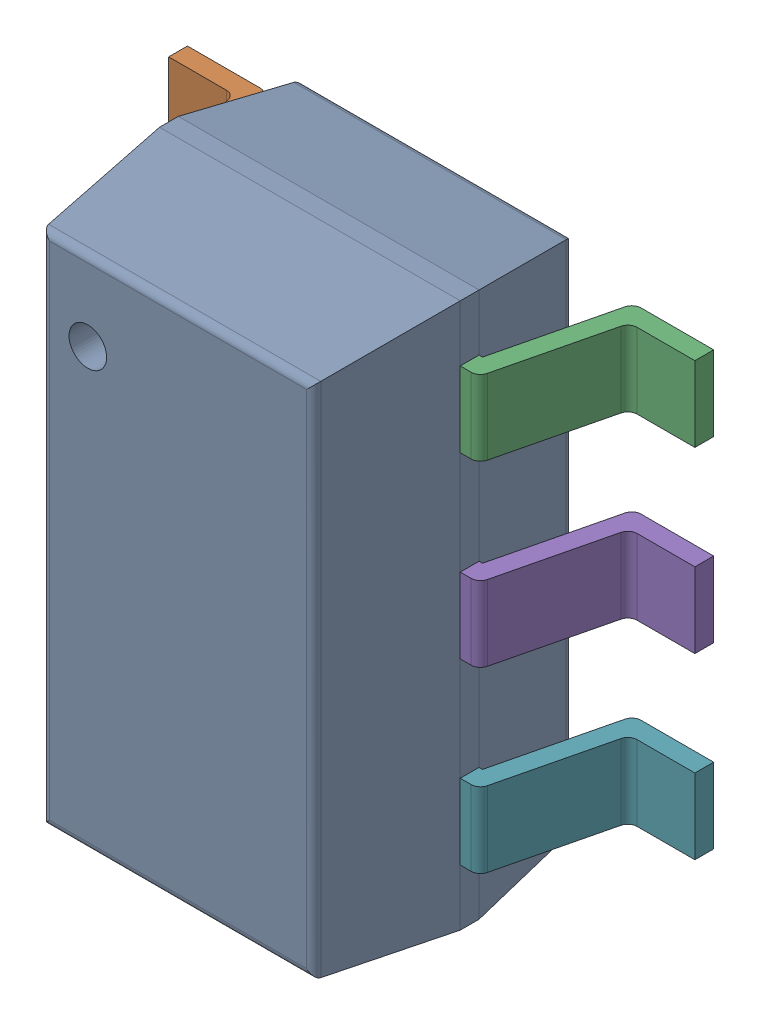
SolidWorks assembly IC21_1.step, configuration Default. Lengths in mm.
Overall size (2.8 2.9 1.45).
3 component instances, 2 part files, 0 mates.
Components (placement in the parent):
- 9798852320_1.step-11: 9798852320_1.step [Default] at (496.9662 325.2319 0) size (2.8 2.9 1.45)
  - Body-7_1.step-11: Body-7_1.step [Default] at origin size (1.6 2.9 1.38)
  - PinsArrayLR-8_1.step-11: PinsArrayLR-8_1.step [Default] at origin size (2.8 2.3 0.75)
